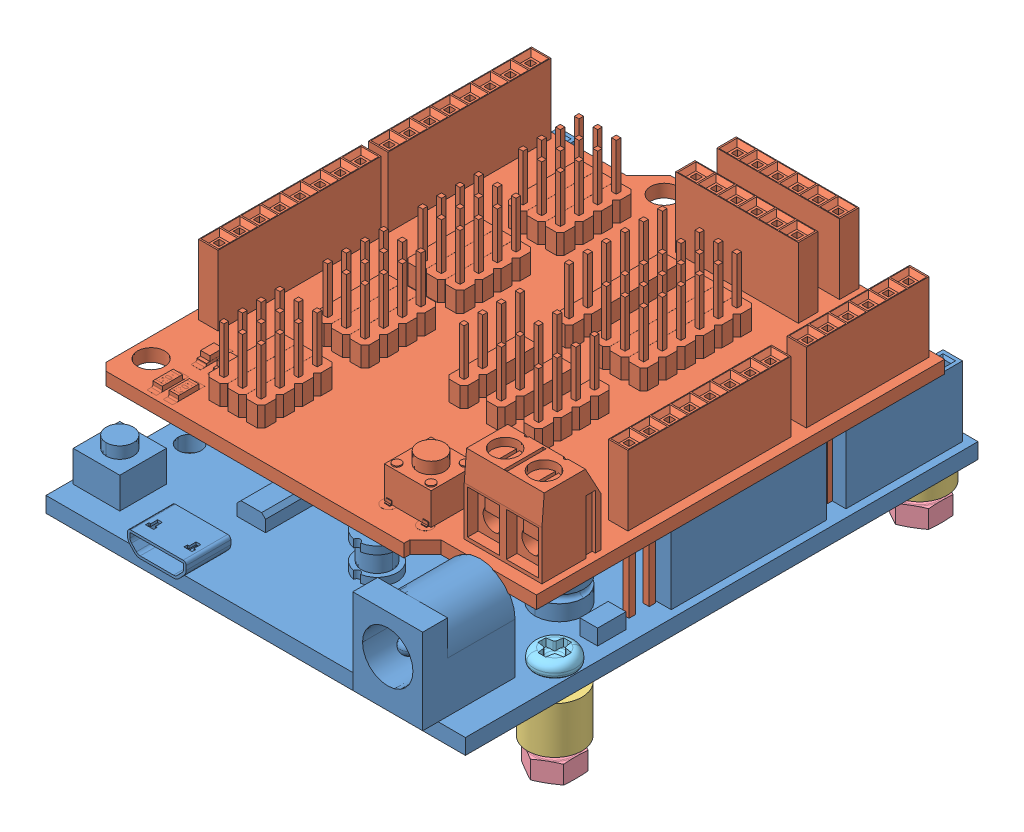
SolidWorks assembly WemosD1R32_WithShield, configuration Predeterminado. Lengths in mm.
Overall size (55.33 32.24 72.84).
11 component instances, 5 part files, 21 mates.
Components (placement in the parent):
- wemosd1r32-1: wemosd1r32 [Predeterminado] at (-5.5887 -7.5717 70.5) size (54 14.5 70.5)
- Arduino Sensor Board V1-1: Arduino Sensor Board V1 [Predeterminado] at (-6.0937 1.4283 68.61) size (53.65 20.91 58.16)
- separador-1: separador [Predeterminado] at (18.9113 -9.5717 90.75) x (1 0 0) z (0 -1 0) size (7 7 6)
- M3 Nut-1: M3 Nut [Predeterminado] at (18.9113 -20.5717 90.75) x (1 0 0) z (0 -1 0) size (6.27 6.27 2.71)
- M3x10 Philips Screw-1: M3x10 Philips Screw [Predeterminado] at (18.9113 -7.5717 90.75) x (1 0 0) z (0 1 0) size (5.3 5.3 11.8)
- M3x10 Philips Screw-2: M3x10 Philips Screw [Predeterminado] at (13.9113 -7.5717 38.75) x (1 0 0) z (0 1 0) size (5.3 5.3 11.8)
- separador-2: separador [Predeterminado] at (13.9113 -9.5717 38.75) x (-0.837169 0 -0.546944) z (0 -1 0) size (7 7 6)
- M3 Nut-2: M3 Nut [Predeterminado] at (13.9113 -20.5717 38.75) x (1 0 0) z (0 -1 0) size (6.27 6.27 2.71)
- M3x10 Philips Screw-3: M3x10 Philips Screw [Predeterminado] at (-14.0887 -7.5717 38.75) x (1 0 0) z (0 1 0) size (5.3 5.3 11.8)
- M3 Nut-3: M3 Nut [Predeterminado] at (-14.0887 -20.5717 38.75) x (1 0 0) z (0 -1 0) size (6.27 6.27 2.71)
- separador-3: separador [Predeterminado] at (-14.0887 -9.5717 38.75) x (1 0 0) z (0 -1 0) size (7 7 6)
Mates (geometry in assembly coordinates):
- Coincidente1: coincident: plane of wemosd1r32-1 through (-30.8387 -7.5717 85) normal (1 0 0); plane of Arduino Sensor Board V1-1 through (-30.8387 1.4283 85) normal (-1 0 0)
- Coincidente2: coincident: plane of wemosd1r32-1 through (-29.8387 -7.5717 85) normal (0 0 -1); plane of Arduino Sensor Board V1-1 through (-30.0387 1.4283 85) normal (0 0 1)
- Coincidente3: coincident: plane of wemosd1r32-1 through (-5.5887 1.4283 70.5) normal (0 1 0); plane of Arduino Sensor Board V1-1 through (-6.0893 1.4283 68.9855) normal (0 -1 0)
- Coincidente4: coincident: plane of wemosd1r32-1 through (-5.5887 -7.5717 70.5) normal (0 1 0); plane of M3x10 Philips Screw-1 through (18.9113 -7.5717 89.15) normal (0 -1 0)
- Concéntrica1: concentric: circle of wemosd1r32-1; circle of M3x10 Philips Screw-1
- Coincidente5: coincident: plane of wemosd1r32-1 through (-5.5887 -9.5717 70.5) normal (0 -1 0); plane of separador-1 through (18.9113 -9.5717 90.75) normal (0 1 0)
- Concéntrica2: concentric: circle of wemosd1r32-1; circle of separador-1
- Distancia1: distance = 1 mm: plane of M3 Nut-1 through (18.9113 -16.5717 90.75) normal (0 1 0); plane of separador-1 through (18.9113 -15.5717 90.75) normal (0 -1 0)
- Concéntrica3: concentric: circle of separador-1; circle of M3 Nut-1
- Coincidente7: coincident: plane of wemosd1r32-1 through (-5.5887 -7.5717 70.5) normal (0 1 0); plane of M3x10 Philips Screw-2 through (13.9113 -7.5717 37.15) normal (0 -1 0)
- Concéntrica4: concentric: circle of wemosd1r32-1; circle of M3x10 Philips Screw-2
- Coincidente8: coincident: plane of wemosd1r32-1 through (-5.5887 -9.5717 70.5) normal (0 -1 0); circle of separador-2
- Concéntrica5: concentric: circle of wemosd1r32-1; circle of separador-2
- Distancia2: distance = 1 mm: plane of M3 Nut-2 through (13.9113 -16.5717 38.75) normal (0 1 0); plane of separador-2 through (13.9113 -15.5717 38.75) normal (0 -1 0)
- Concéntrica6: concentric: circle of separador-2; circle of M3 Nut-2
- Coincidente10: coincident: plane of wemosd1r32-1 through (-5.5887 -7.5717 70.5) normal (0 1 0); plane of M3x10 Philips Screw-3 through (-14.0887 -7.5717 37.15) normal (0 -1 0)
- Concéntrica7: concentric: circle of wemosd1r32-1; circle of M3x10 Philips Screw-3
- Coincidente11: coincident: plane of wemosd1r32-1 through (-5.5887 -9.5717 70.5) normal (0 -1 0); plane of separador-3 through (-14.0887 -9.5717 38.75) normal (0 1 0)
- Concéntrica8: concentric: circle of wemosd1r32-1; circle of separador-3
- Concéntrica9: concentric: circle of M3 Nut-3; circle of separador-3
- Distancia3: distance = 1 mm: plane of M3 Nut-3 through (-14.0887 -16.5717 38.75) normal (0 1 0); plane of separador-3 through (-14.0887 -15.5717 38.75) normal (0 -1 0)
